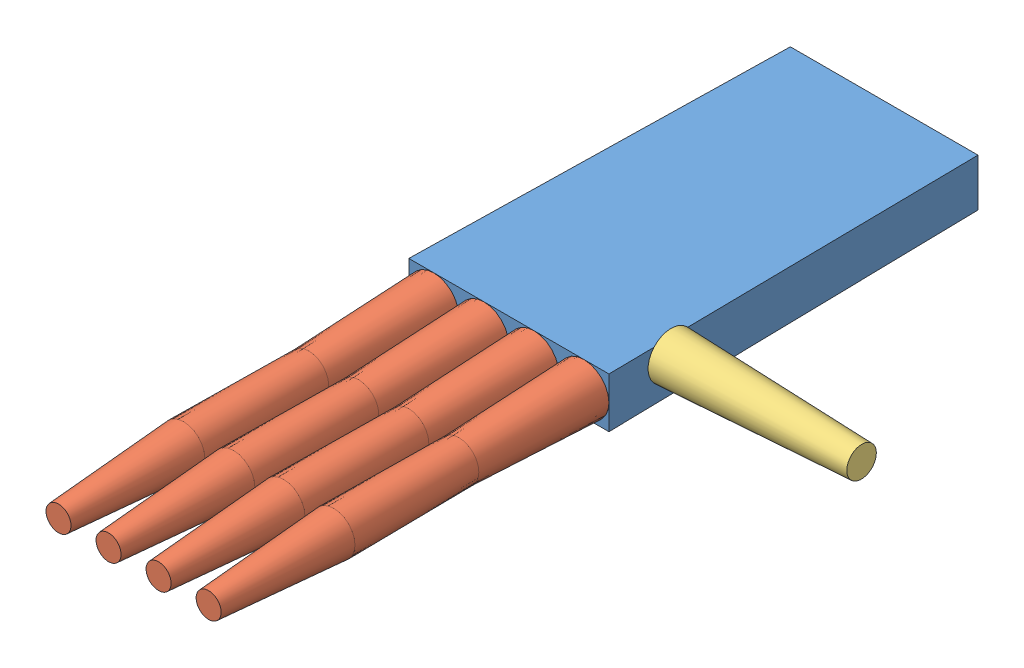
SolidWorks assembly Assem2, configuration Default. Lengths in mm.
Overall size (309.55 52.06 600).
6 component instances, 3 part files, 8 mates.
Components (placement in the parent):
- Handbase-mpang-1: Handbase-mpang [Default] at (164.4806 233.0279 150.6195) size (160 40 300)
- Finger-mpang-1: Finger-mpang [Default] at (104.4806 233.0279 450.6195) size (40 40 300)
- Finger-mpang-2: Finger-mpang [Default] at (144.4806 233.0279 450.6195) size (40 40 300)
- Finger-mpang-3: Finger-mpang [Default] at (184.4806 233.0279 450.6195) size (40 40 300)
- Finger-mpang-4: Finger-mpang [Default] at (224.4806 233.0279 450.6195) size (40 40 300)
- Thumb3-mpang-1: Thumb3-mpang [Default] at (243.6427 240.4537 400.3427) x (-0.00712 -0.904123 -0.427214) z (0.999861 0 -0.016664) size (37 37 150)
Mates (geometry in assembly coordinates):
- Coincident2: coincident aligned: circle of Handbase-mpang-1; circle of Finger-mpang-1
- Lock1: lock: unknown of Handbase-mpang-1; unknown of Finger-mpang-1
- Coincident6: coincident: circle of Handbase-mpang-1; circle of Finger-mpang-2
- Lock2: lock: unknown of Handbase-mpang-1; unknown of Finger-mpang-2
- Coincident7: coincident aligned: circle of Handbase-mpang-1; circle of Finger-mpang-3
- Coincident8: coincident: circle of Handbase-mpang-1; circle of Finger-mpang-4
- Lock3: lock: unknown of Handbase-mpang-1; unknown of Finger-mpang-4
- Coincident9: coincident aligned: plane of Handbase-mpang-1 through (239.4598 233.0279 149.3699) normal (0.999861 0 -0.016664); circle of Thumb3-mpang-1
